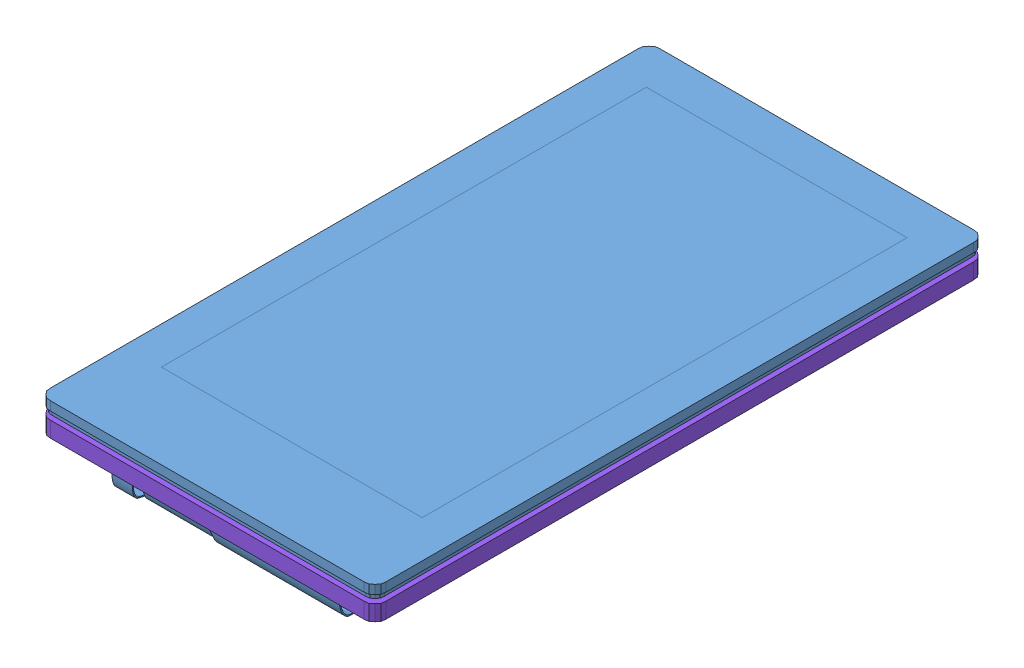
SolidWorks assembly SF-TC190B-8822A, configuration Standard. Lengths in mm.
Overall size (30 6.5 54.5).
47 component instances, 8 part files, 18 mates.
Components (placement in the parent):
- SF-TC190B-8822A-1: SF-TC190B-8822A [Standard] at origin size (30 5.83 54.5)
- User Library-QFN40-1: User Library-QFN40 [По умолчанию] at (5.4891 -1.8 19.7911) x (0 0 -1) z (-1 0 0) size (6 0.8 6)
- 742843122-1: 742843122 [Standard] at (1.2743 -2.05 14.647) x (1 0 0) z (0 -1 0) size (0.5 1 0.5)
- 742843122-2: 742843122 [Standard] at (4.481 -2.05 14.647) x (1 0 0) z (0 -1 0) size (0.5 1 0.5)
- 742843122-3: 742843122 [Standard] at (9.1154 -2.05 14.647) x (1 0 0) z (0 -1 0) size (0.5 1 0.5)
- 742843122-4: 742843122 [Standard] at (10.1392 -2.05 14.647) x (1 0 0) z (0 -1 0) size (0.5 1 0.5)
- 742843122-5: 742843122 [Standard] at (2.259 -2.05 14.647) x (1 0 0) z (0 -1 0) size (0.5 1 0.5)
- 742843122-6: 742843122 [Standard] at (3.3721 -2.05 14.647) x (1 0 0) z (0 -1 0) size (0.5 1 0.5)
- 742843122-7: 742843122 [Standard] at (8.0513 -2.05 14.647) x (1 0 0) z (0 -1 0) size (0.5 1 0.5)
- 20436_ACF-050-30-C-CMS-H-1: 20436_ACF-050-30-C-CMS-H [Standard] at (7.1642 -1.6 3.2797) x (-1 0 -0.000021) z (-0.000021 0 1) size (20.5 2 5)
  - 20436_ACF-050-30-C-CMS-H.stp-1: 20436_ACF-050-30-C-CMS-H.stp [Standard] at origin size (20.5 2 5)
    - ANTELEC-FFC-P281-C-1R.stp-1: ANTELEC-FFC-P281-C-1R.stp [Standard] at origin size (20.5 2 5)
      - Broche P281 H.stp-1: Broche P281 H.stp [Standard] at (14.75 1 1.3) x (0 -1 0) z (-1 0 0) size (2 4.79 0.2)
      - Broche P281 H.stp-2: Broche P281 H.stp [Standard] at (4.25 1 1.3) x (0 -1 0) z (-1 0 0) size (2 4.79 0.2)
      - Broche P281 H.stp-3: Broche P281 H.stp [Standard] at (15.25 1 1.3) x (0 -1 0) z (-1 0 0) size (2 4.79 0.2)
      - Broche P281 H.stp-4: Broche P281 H.stp [Standard] at (3.75 1 1.3) x (0 -1 0) z (-1 0 0) size (2 4.79 0.2)
      - Broche P281 H.stp-5: Broche P281 H.stp [Standard] at (15.75 1 1.3) x (0 -1 0) z (-1 0 0) size (2 4.79 0.2)
      - Broche P281 H.stp-6: Broche P281 H.stp [Standard] at (3.25 1 1.3) x (0 -1 0) z (-1 0 0) size (2 4.79 0.2)
      - Broche P281 H.stp-7: Broche P281 H.stp [Standard] at (9.75 1 1.3) x (0 -1 0) z (-1 0 0) size (2 4.79 0.2)
      - Broche P281 H.stp-8: Broche P281 H.stp [Standard] at (9.25 1 1.3) x (0 -1 0) z (-1 0 0) size (2 4.79 0.2)
      - Broche P281 H.stp-9: Broche P281 H.stp [Standard] at (10.25 1 1.3) x (0 -1 0) z (-1 0 0) size (2 4.79 0.2)
      - Broche P281 H.stp-10: Broche P281 H.stp [Standard] at (8.75 1 1.3) x (0 -1 0) z (-1 0 0) size (2 4.79 0.2)
      - Broche P281 H.stp-11: Broche P281 H.stp [Standard] at (10.75 1 1.3) x (0 -1 0) z (-1 0 0) size (2 4.79 0.2)
      - Broche P281 H.stp-12: Broche P281 H.stp [Standard] at (8.25 1 1.3) x (0 -1 0) z (-1 0 0) size (2 4.79 0.2)
      - Broche P281 H.stp-13: Broche P281 H.stp [Standard] at (11.25 1 1.3) x (0 -1 0) z (-1 0 0) size (2 4.79 0.2)
      - Broche P281 H.stp-14: Broche P281 H.stp [Standard] at (7.75 1 1.3) x (0 -1 0) z (-1 0 0) size (2 4.79 0.2)
      - Broche P281 H.stp-15: Broche P281 H.stp [Standard] at (11.75 1 1.3) x (0 -1 0) z (-1 0 0) size (2 4.79 0.2)
      - Broche P281 H.stp-16: Broche P281 H.stp [Standard] at (7.25 1 1.3) x (0 -1 0) z (-1 0 0) size (2 4.79 0.2)
      - Broche P281 H.stp-17: Broche P281 H.stp [Standard] at (12.25 1 1.3) x (0 -1 0) z (-1 0 0) size (2 4.79 0.2)
      - Broche P281 H.stp-18: Broche P281 H.stp [Standard] at (6.75 1 1.3) x (0 -1 0) z (-1 0 0) size (2 4.79 0.2)
      - Broche P281 H.stp-19: Broche P281 H.stp [Standard] at (12.75 1 1.3) x (0 -1 0) z (-1 0 0) size (2 4.79 0.2)
      - Broche P281 H.stp-20: Broche P281 H.stp [Standard] at (6.25 1 1.3) x (0 -1 0) z (-1 0 0) size (2 4.79 0.2)
      - Broche P281 H.stp-21: Broche P281 H.stp [Standard] at (13.25 1 1.3) x (0 -1 0) z (-1 0 0) size (2 4.79 0.2)
      - Broche P281 H.stp-22: Broche P281 H.stp [Standard] at (5.75 1 1.3) x (0 -1 0) z (-1 0 0) size (2 4.79 0.2)
      - Broche P281 H.stp-23: Broche P281 H.stp [Standard] at (13.75 1 1.3) x (0 -1 0) z (-1 0 0) size (2 4.79 0.2)
      - Broche P281 H.stp-24: Broche P281 H.stp [Standard] at (5.25 1 1.3) x (0 -1 0) z (-1 0 0) size (2 4.79 0.2)
      - Broche P281 H.stp-25: Broche P281 H.stp [Standard] at (14.25 1 1.3) x (0 -1 0) z (-1 0 0) size (2 4.79 0.2)
      - Broche P281 H.stp-26: Broche P281 H.stp [Standard] at (4.75 1 1.3) x (0 -1 0) z (-1 0 0) size (2 4.79 0.2)
      - Broche P281 H.stp-27: Broche P281 H.stp [Standard] at (16.25 1 1.3) x (0 -1 0) z (-1 0 0) size (2 4.79 0.2)
      - Broche P281 H.stp-28: Broche P281 H.stp [Standard] at (2.75 1 1.3) x (0 -1 0) z (-1 0 0) size (2 4.79 0.2)
      - Broche P281 H.stp-29: Broche P281 H.stp [Standard] at (16.75 1 1.3) x (0 -1 0) z (-1 0 0) size (2 4.79 0.2)
      - Broche P281 H.stp-30: Broche P281 H.stp [Standard] at (2.25 1 1.3) x (0 -1 0) z (-1 0 0) size (2 4.79 0.2)
      - Partie métallique P281.stp-1: Partie métallique P281.stp [Standard] at (18 1 -0.2) x (0 -1 0) z (0 0 1) size (2 1.8 3.1)
      - Partie métallique P281.stp-2: Partie métallique P281.stp [Standard] at (0.8 1 -0.2) x (0 1 0) z (0 0 1) size (2 1.8 3.1)
      - Capot P281-C-1R.stp-1: Capot P281-C-1R.stp [Standard] at (9.4 1 0.9) x (-1 0 0) z (0 0 1) size (20.5 2 3)
      - Isolant P281-C-1R.stp-1: Isolant P281-C-1R.stp [Standard] at (9.4 1 0) size (18.8 2 3.9)
- Spacer-1: Spacer [Standard] at origin size (30 1.4 54.5)
Mates (geometry in assembly coordinates):
- Deckungsgleich1: coincident: plane of SF-TC190B-8822A-1 through (0 -1.8 0) normal (0 -1 0); plane of User Library-QFN40-1 through (7.7891 -1.8 17.4911) normal (0 1 0)
- Parallel1: parallel aligned: plane of SF-TC190B-8822A-1 through (-0.1027 12.1232 27.7674) normal (-1 0 0); plane of User Library-QFN40-1 through (2.4891 -2.6 22.7911) normal (-1 0 0)
- Deckungsgleich3: coincident anti-aligned: plane of SF-TC190B-8822A-1 through (0 -1.8 0) normal (0 -1 0); plane of 742843122-1 through (1.0243 -1.8 14.397) normal (0 1 0)
- Parallel2: parallel aligned: plane of User Library-QFN40-1 through (2.4891 -2.6 22.7911) normal (-1 0 0); plane of 742843122-1 through (1.0243 -2.3 14.897) normal (-1 0 0)
- Deckungsgleich5: coincident anti-aligned: plane of SF-TC190B-8822A-1 through (0 -1.8 0) normal (0 -1 0); plane of 742843122-2 through (4.231 -1.8 14.397) normal (0 1 0)
- Deckungsgleich6: coincident anti-aligned: plane of SF-TC190B-8822A-1 through (0 -1.8 0) normal (0 -1 0); plane of 742843122-3 through (8.8654 -1.8 14.397) normal (0 1 0)
- Deckungsgleich7: coincident anti-aligned: plane of SF-TC190B-8822A-1 through (0 -1.8 0) normal (0 -1 0); plane of 742843122-4 through (9.8892 -1.8 14.397) normal (0 1 0)
- Deckungsgleich8: coincident anti-aligned: plane of SF-TC190B-8822A-1 through (0 -1.8 0) normal (0 -1 0); plane of 742843122-5 through (2.009 -1.8 14.397) normal (0 1 0)
- Deckungsgleich9: coincident anti-aligned: plane of SF-TC190B-8822A-1 through (0 -1.8 0) normal (0 -1 0); plane of 742843122-6 through (3.1221 -1.8 14.397) normal (0 1 0)
- Deckungsgleich10: coincident aligned: plane of 742843122-1 through (1.0243 -1.8 14.147) normal (0 0 -1); plane of 742843122-6 through (3.1221 -1.8 14.147) normal (0 0 -1)
- Deckungsgleich11: coincident aligned: plane of 742843122-2 through (4.231 -1.8 14.147) normal (0 0 -1); plane of 742843122-6 through (3.1221 -1.8 14.147) normal (0 0 -1)
- Deckungsgleich12: coincident aligned: plane of 742843122-2 through (4.231 -1.8 14.147) normal (0 0 -1); plane of 742843122-5 through (2.009 -1.8 14.147) normal (0 0 -1)
- Deckungsgleich13: coincident aligned: plane of 742843122-2 through (4.231 -1.8 14.147) normal (0 0 -1); plane of 742843122-3 through (8.8654 -1.8 14.147) normal (0 0 -1)
- Deckungsgleich14: coincident aligned: plane of 742843122-4 through (9.8892 -1.8 14.147) normal (0 0 -1); plane of 742843122-6 through (3.1221 -1.8 14.147) normal (0 0 -1)
- Deckungsgleich15: coincident anti-aligned: plane of SF-TC190B-8822A-1 through (0 -1.8 0) normal (0 -1 0); plane of 742843122-7 through (7.8013 -1.8 14.397) normal (0 1 0)
- Deckungsgleich16: coincident aligned: plane of 742843122-2 through (4.231 -1.8 14.147) normal (0 0 -1); plane of 742843122-7 through (7.8013 -1.8 14.147) normal (0 0 -1)
- Deckungsgleich17: coincident: plane of SF-TC190B-8822A-1 through (0 -1.6 0) normal (0 1 0); plane of 20436_ACF-050-30-C-CMS-H-1/20436_ACF-050-30-C-CMS-H.stp-1/ANTELEC-FFC-P281-C-1R.stp-1/Broche P281 H.stp-30 through (5.1142 -1.6 4.5797) normal (0 1 0)
- Breite2: width anti-aligned: plane of 20436_ACF-050-30-C-CMS-H-1/20436_ACF-050-30-C-CMS-H.stp-1/ANTELEC-FFC-P281-C-1R.stp-1/Partie métallique P281.stp-1 through (-11.7358 -2.6 6.1793) normal (-1 0 -0.000021); plane of 20436_ACF-050-30-C-CMS-H-1/20436_ACF-050-30-C-CMS-H.stp-1/ANTELEC-FFC-P281-C-1R.stp-1/Partie métallique P281.stp-2 through (7.2642 -2.6 6.1797) normal (1 0 0.000021); plane of SF-TC190B-8822A-1 through (5.5349 -2.85 0.0002) normal (1 0 0.000036); plane of SF-TC190B-8822A-1 through (-10.0063 -2.85 -0.0001) normal (-1 0 -0.000006)
